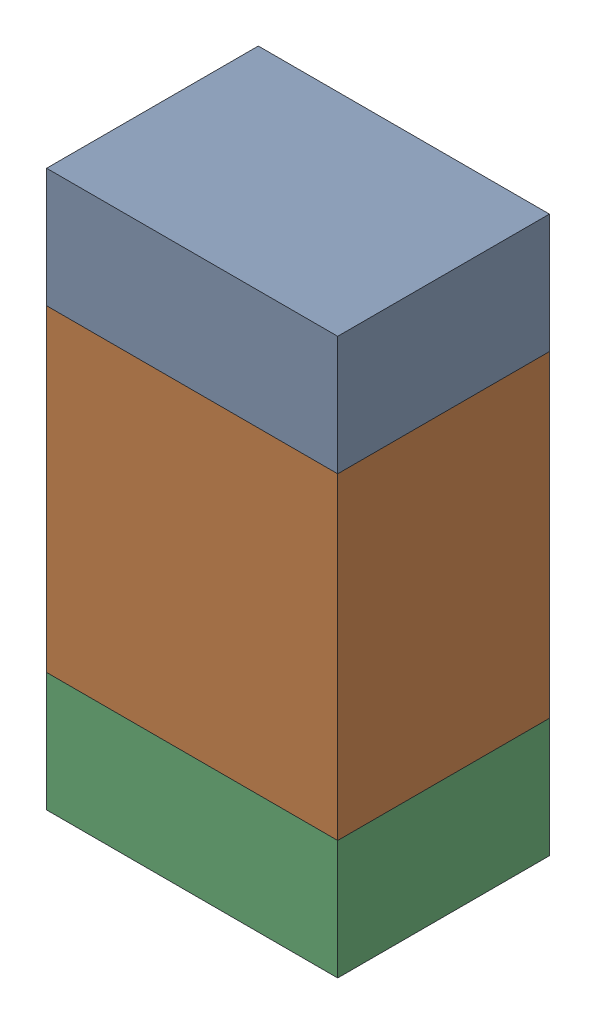
SolidWorks assembly R303_1PCB, configuration Default. Lengths in mm.
Overall size (0.55 1.05 0.4).
6 component instances, 2 part files, 0 mates.
Components (placement in the parent):
- 846483288-1: 846483288 [Default] at (143.3999 104.4124 0) size (0.55 0.22 0.4)
  - Extruded_12-1: Extruded_12 [Default] at origin size (0.55 0.22 0.4)
- 846483424-1: 846483424 [Default] at (143.3999 103.9999 0) size (0.55 0.6 0.4)
  - Extruded_13-1: Extruded_13 [Default] at origin size (0.55 0.6 0.4)
- 846483288-2: 846483288 [Default] at (143.3999 103.5874 0) size (0.55 0.22 0.4)
  - Extruded_12-1: Extruded_12 [Default] at origin size (0.55 0.22 0.4)
